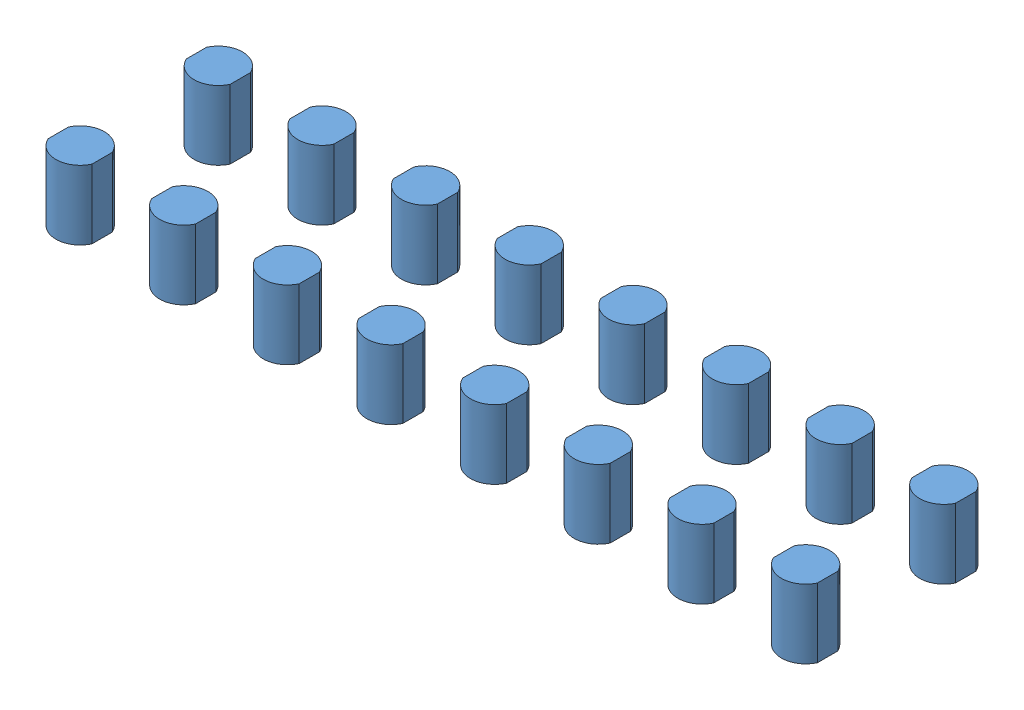
SolidWorks assembly lemo_cutouts, configuration Default. Lengths in mm.
Overall size (111.35 10 27).
16 component instances, 1 part files, 47 mates.
Components (placement in the parent):
- lemo-1: lemo [Default] at (5.3591 2.4596 8.6921) size (6.35 10 7)
- lemo-2: lemo [Default] at (5.3591 2.4596 28.6921) size (6.35 10 7)
- lemo-3: lemo [Default] at (20.3591 2.4596 28.6921) size (6.35 10 7)
- lemo-4: lemo [Default] at (20.3591 2.4596 8.6921) size (6.35 10 7)
- lemo-5: lemo [Default] at (35.3591 2.4596 28.6921) size (6.35 10 7)
- lemo-6: lemo [Default] at (50.3591 2.4596 28.6921) size (6.35 10 7)
- lemo-7: lemo [Default] at (50.3591 2.4596 8.6921) size (6.35 10 7)
- lemo-8: lemo [Default] at (35.3591 2.4596 8.6921) size (6.35 10 7)
- lemo-9: lemo [Default] at (65.3591 2.4596 28.6921) size (6.35 10 7)
- lemo-10: lemo [Default] at (95.3591 2.4596 8.6921) size (6.35 10 7)
- lemo-11: lemo [Default] at (80.3591 2.4596 28.6921) size (6.35 10 7)
- lemo-12: lemo [Default] at (80.3591 2.4596 8.6921) size (6.35 10 7)
- lemo-13: lemo [Default] at (110.3591 2.4596 28.6921) size (6.35 10 7)
- lemo-14: lemo [Default] at (65.3591 2.4596 8.6921) size (6.35 10 7)
- lemo-15: lemo [Default] at (95.3591 2.4596 28.6921) size (6.35 10 7)
- lemo-16: lemo [Default] at (110.3591 2.4596 8.6921) size (6.35 10 7)
Mates (geometry in assembly coordinates):
- Coincident2: coincident aligned: plane of lemo-1 through (5.3591 12.4596 8.6921) normal (0 1 0); plane of lemo-2 through (5.3591 12.4596 28.6921) normal (0 1 0)
- Coincident4: coincident aligned: plane of lemo-1 through (8.5354 12.4596 8.6921) normal (1 0 0); plane of lemo-2 through (8.5354 12.4596 28.6921) normal (1 0 0)
- Distance2: distance = 20 mm: line of lemo-2 through (8.5354 12.4596 30.1621) axis (0 -1 0); line of lemo-1 through (8.5354 12.4596 10.1621) axis (0 -1 0)
- Coincident6: coincident aligned: plane of lemo-3 through (23.5354 12.4596 28.6921) normal (1 0 0); plane of lemo-4 through (23.5354 12.4596 8.6921) normal (1 0 0)
- Coincident7: coincident aligned: plane of lemo-3 through (20.3591 12.4596 28.6921) normal (0 1 0); plane of lemo-4 through (20.3591 12.4596 8.6921) normal (0 1 0)
- Distance3: distance = 20 mm: line of lemo-3 through (23.5354 12.4596 30.1621) axis (0 -1 0); line of lemo-4 through (23.5354 12.4596 10.1621) axis (0 -1 0)
- Distance4: distance = 15 mm aligned: plane of lemo-4 through (23.5354 12.4596 8.6921) normal (1 0 0); plane of lemo-1 through (8.5354 12.4596 8.6921) normal (1 0 0)
- Coincident9: coincident aligned: plane of lemo-1 through (5.3591 12.4596 8.6921) normal (0 1 0); plane of lemo-4 through (20.3591 12.4596 8.6921) normal (0 1 0)
- Distance5: distance = 15 mm: line of lemo-4 through (23.5354 12.4596 7.2221) axis (0 -1 0); line of lemo-1 through (8.5354 12.4596 7.2221) axis (0 -1 0)
- Coincident11: coincident aligned: plane of lemo-5 through (38.5354 12.4596 28.6921) normal (1 0 0); plane of lemo-8 through (38.5354 12.4596 8.6921) normal (1 0 0)
- Distance6: distance = 15 mm: line of lemo-7 through (53.5354 12.4596 7.2221) axis (0 -1 0); line of lemo-8 through (38.5354 12.4596 7.2221) axis (0 -1 0)
- Coincident12: coincident aligned: plane of lemo-6 through (53.5354 12.4596 28.6921) normal (1 0 0); plane of lemo-7 through (53.5354 12.4596 8.6921) normal (1 0 0)
- Coincident13: coincident aligned: plane of lemo-5 through (35.3591 12.4596 28.6921) normal (0 1 0); plane of lemo-8 through (35.3591 12.4596 8.6921) normal (0 1 0)
- Coincident14: coincident aligned: plane of lemo-6 through (50.3591 12.4596 28.6921) normal (0 1 0); plane of lemo-7 through (50.3591 12.4596 8.6921) normal (0 1 0)
- Distance7: distance = 20 mm: line of lemo-6 through (53.5354 12.4596 30.1621) axis (0 -1 0); line of lemo-7 through (53.5354 12.4596 10.1621) axis (0 -1 0)
- Distance8: distance = 20 mm: line of lemo-5 through (38.5354 12.4596 30.1621) axis (0 -1 0); line of lemo-8 through (38.5354 12.4596 10.1621) axis (0 -1 0)
- Coincident15: coincident aligned: plane of lemo-7 through (50.3591 12.4596 8.6921) normal (0 1 0); plane of lemo-8 through (35.3591 12.4596 8.6921) normal (0 1 0)
- Distance9: distance = 15 mm aligned: plane of lemo-7 through (53.5354 12.4596 8.6921) normal (1 0 0); plane of lemo-8 through (38.5354 12.4596 8.6921) normal (1 0 0)
- Coincident17: coincident aligned: plane of lemo-4 through (20.3591 12.4596 8.6921) normal (0 1 0); plane of lemo-8 through (35.3591 12.4596 8.6921) normal (0 1 0)
- Parallel4: parallel aligned: plane of lemo-4 through (23.5354 12.4596 8.6921) normal (1 0 0); plane of lemo-8 through (38.5354 12.4596 8.6921) normal (1 0 0)
- Distance11: distance = 15 mm aligned: plane of lemo-8 through (38.5354 12.4596 8.6921) normal (1 0 0); plane of lemo-4 through (23.5354 12.4596 8.6921) normal (1 0 0)
- Distance12: distance = 15 mm: line of lemo-8 through (38.5354 12.4596 7.2221) axis (0 -1 0); line of lemo-4 through (23.5354 12.4596 7.2221) axis (0 -1 0)
- Coincident22: coincident aligned: plane of lemo-10 through (95.3591 12.4596 45.3022) normal (0 1 0); plane of lemo-12 through (80.3591 12.4596 45.3022) normal (0 1 0)
- Distance13: distance = 15 mm aligned: plane of lemo-10 through (98.5354 12.4596 8.6921) normal (1 0 0); plane of lemo-12 through (83.5354 12.4596 8.6921) normal (1 0 0)
- Distance14: distance = 15 mm: line of lemo-10 through (98.5354 12.4596 7.2221) axis (0 -1 0); line of lemo-12 through (83.5354 12.4596 7.2221) axis (0 -1 0)
- Coincident23: coincident aligned: plane of lemo-9 through (68.5354 12.4596 65.3022) normal (1 0 0); plane of lemo-14 through (68.5354 12.4596 45.3022) normal (1 0 0)
- Coincident24: coincident aligned: plane of lemo-13 through (113.5354 12.4596 65.3022) normal (1 0 0); plane of lemo-16 through (113.5354 12.4596 45.3022) normal (1 0 0)
- Distance15: distance = 15 mm: line of lemo-12 through (83.5354 12.4596 7.2221) axis (0 -1 0); line of lemo-14 through (68.5354 12.4596 7.2221) axis (0 -1 0)
- Coincident25: coincident aligned: plane of lemo-11 through (83.5354 12.4596 65.3022) normal (1 0 0); plane of lemo-12 through (83.5354 12.4596 45.3022) normal (1 0 0)
- Coincident26: coincident aligned: plane of lemo-9 through (65.3591 12.4596 65.3022) normal (0 1 0); plane of lemo-14 through (65.3591 12.4596 45.3022) normal (0 1 0)
- Coincident27: coincident aligned: plane of lemo-11 through (80.3591 12.4596 65.3022) normal (0 1 0); plane of lemo-12 through (80.3591 12.4596 45.3022) normal (0 1 0)
- Distance16: distance = 20 mm: line of lemo-11 through (83.5354 12.4596 30.1621) axis (0 -1 0); line of lemo-12 through (83.5354 12.4596 10.1621) axis (0 -1 0)
- Coincident28: coincident aligned: plane of lemo-10 through (98.5354 12.4596 45.3022) normal (1 0 0); plane of lemo-15 through (98.5354 12.4596 65.3022) normal (1 0 0)
- Distance17: distance = 20 mm: line of lemo-9 through (68.5354 12.4596 30.1621) axis (0 -1 0); line of lemo-14 through (68.5354 12.4596 10.1621) axis (0 -1 0)
- Coincident29: coincident aligned: plane of lemo-12 through (80.3591 12.4596 45.3022) normal (0 1 0); plane of lemo-14 through (65.3591 12.4596 45.3022) normal (0 1 0)
- Distance18: distance = 15 mm: line of lemo-16 through (113.5354 12.4596 7.2221) axis (0 -1 0); line of lemo-10 through (98.5354 12.4596 7.2221) axis (0 -1 0)
- Distance19: distance = 15 mm aligned: plane of lemo-12 through (83.5354 12.4596 8.6921) normal (1 0 0); plane of lemo-14 through (68.5354 12.4596 8.6921) normal (1 0 0)
- Coincident30: coincident aligned: plane of lemo-10 through (95.3591 12.4596 45.3022) normal (0 1 0); plane of lemo-15 through (95.3591 12.4596 65.3022) normal (0 1 0)
- Coincident31: coincident aligned: plane of lemo-13 through (110.3591 12.4596 65.3022) normal (0 1 0); plane of lemo-16 through (110.3591 12.4596 45.3022) normal (0 1 0)
- Distance20: distance = 20 mm: line of lemo-15 through (98.5354 12.4596 30.1621) axis (0 -1 0); line of lemo-10 through (98.5354 12.4596 10.1621) axis (0 -1 0)
- Coincident32: coincident aligned: plane of lemo-10 through (95.3591 12.4596 45.3022) normal (0 1 0); plane of lemo-16 through (110.3591 12.4596 45.3022) normal (0 1 0)
- Distance21: distance = 15 mm aligned: plane of lemo-16 through (113.5354 12.4596 8.6921) normal (1 0 0); plane of lemo-10 through (98.5354 12.4596 8.6921) normal (1 0 0)
- Distance22: distance = 20 mm: line of lemo-13 through (113.5354 12.4596 30.1621) axis (0 -1 0); line of lemo-16 through (113.5354 12.4596 10.1621) axis (0 -1 0)
- Parallel6: parallel aligned: plane of lemo-10 through (98.5354 12.4596 45.3022) normal (1 0 0); plane of lemo-12 through (83.5354 12.4596 45.3022) normal (1 0 0)
- Coincident33: coincident aligned: plane of lemo-7 through (50.3591 12.4596 8.6921) normal (0 1 0); plane of lemo-14 through (65.3591 12.4596 45.3022) normal (0 1 0)
- Distance23: distance = 15 mm aligned: plane of lemo-14 through (68.5354 12.4596 8.6921) normal (1 0 0); plane of lemo-7 through (53.5354 12.4596 8.6921) normal (1 0 0)
- Distance24: distance = 15 mm: line of lemo-14 through (68.5354 12.4596 7.2221) axis (0 -1 0); line of lemo-7 through (53.5354 12.4596 7.2221) axis (0 -1 0)
